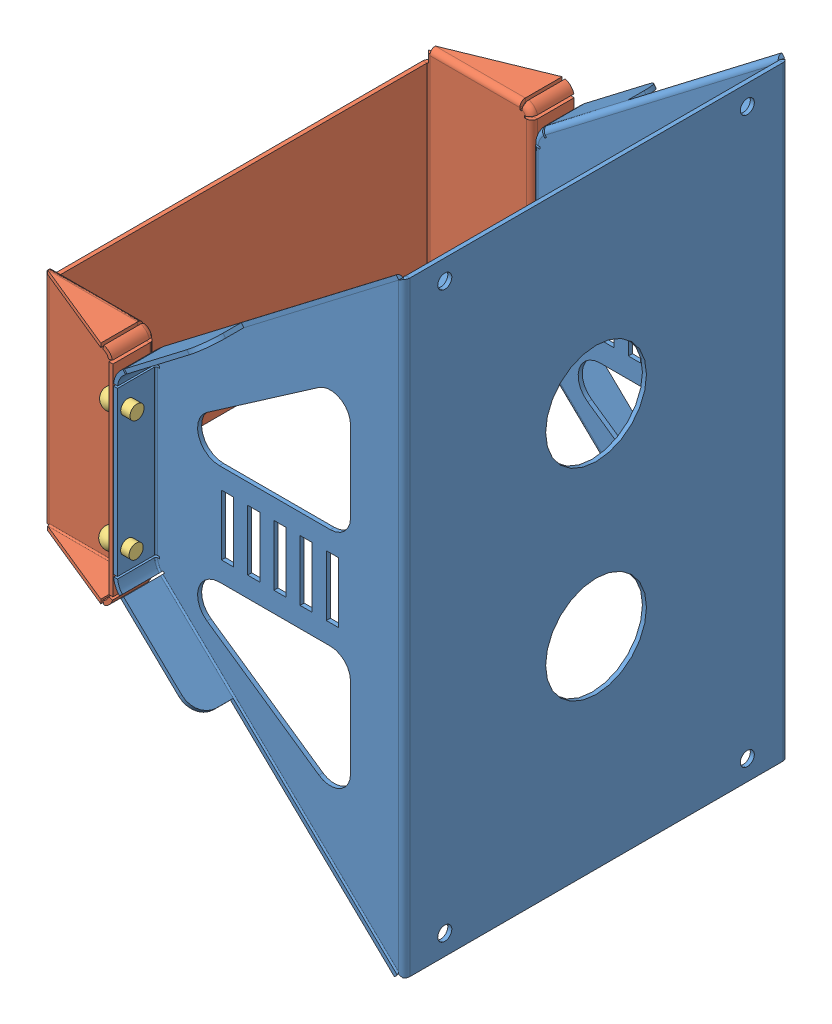
SolidWorks assembly car battery bracket, configuration Default. Lengths in mm.
Overall size (178.58 301.33 232.11).
6 component instances, 3 part files, 6 mates.
Components (placement in the parent):
- lower car battery bracket-1: lower car battery bracket [Default] at origin size (125.21 301.33 228.47)
- car battery upper body-1: car battery upper body [Default] at (-363.8343 11.4971 -0.018) size (53.37 112 228.75)
- rivet-1: rivet [Default] at (-223.2358 41.4971 -15.6454) x (0 0.980538 -0.19633) z (0 0.19633 0.980538) size (10 16.41 10)
- rivet-2: rivet [Default] at (-223.0501 -18.5029 -15.6454) x (0 0.637204 0.770695) z (0 -0.770695 0.637204) size (10 16.41 10)
- rivet-3: rivet [Default] at (-222.7383 41.4971 202.3546) x (0 0.693121 0.720821) z (0 -0.720821 0.693121) size (10 16.41 10)
- rivet-4: rivet [Default] at (-223.1857 -18.5029 202.3546) x (0 -0.321822 -0.9468) z (0 0.9468 -0.321822) size (10 16.41 10)
Mates (geometry in assembly coordinates):
- Coincident2: coincident anti-aligned: plane of lower car battery bracket-1 through (-217.8343 0 0) normal (-1 0 0); plane of car battery upper body-1 through (-217.8343 11.4971 -0.018) normal (1 0 0)
- Coincident3: coincident anti-aligned: axis of lower car battery bracket-1 through (-217.8343 41.4971 202.3546) axis (1 0 0); axis of car battery upper body-1 through (-217.8343 41.4971 202.3546) axis (-1 0 0)
- Coincident7: coincident aligned: axis of car battery upper body-1 through (-217.8343 41.4971 -15.6454) axis (-1 0 0); axis of rivet-1 through (-211.7358 41.4971 -15.6454) axis (-1 0 0)
- Coincident13: coincident aligned: axis of car battery upper body-1 through (-217.8343 -18.5029 -15.6454) axis (-1 0 0); axis of rivet-2 through (-211.5501 -18.5029 -15.6454) axis (-1 0 0)
- Coincident14: coincident aligned: axis of car battery upper body-1 through (-217.8343 41.4971 202.3546) axis (-1 0 0); axis of rivet-3 through (-211.2383 41.4971 202.3546) axis (-1 0 0)
- Coincident15: coincident aligned: axis of car battery upper body-1 through (-217.8343 -18.5029 202.3546) axis (-1 0 0); axis of rivet-4 through (-211.6857 -18.5029 202.3546) axis (-1 0 0)
